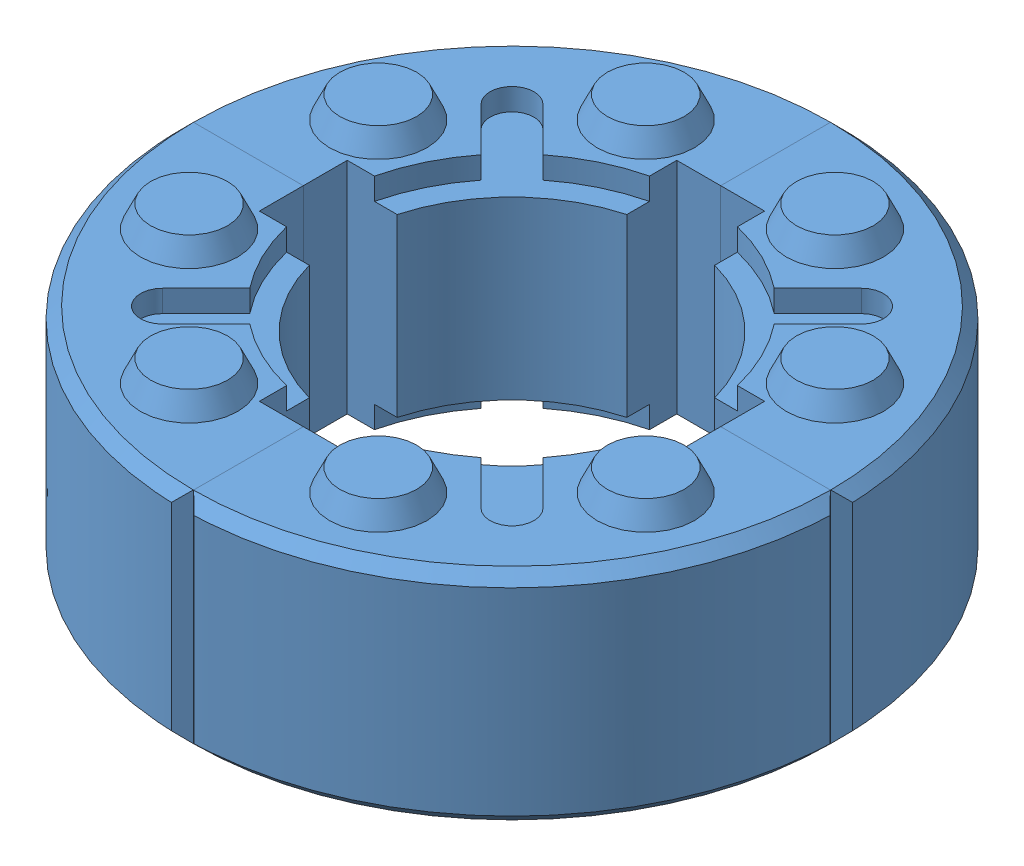
SolidWorks assembly Assem1, configuration Default. Lengths in mm.
Overall size (299.82 110 299.82).
4 component instances, 1 part files, 6 mates.
Components (placement in the parent):
- pillar brick 300dia-1: pillar brick 300dia [Default] at (-142.4139 -67.4386 119.003) size (149.91 110 149.91)
- pillar brick 300dia-2: pillar brick 300dia [Default] at (-142.4139 -67.4386 119.003) x (0 0 -1) z (1 0 0) size (149.91 110 149.91)
- pillar brick 300dia-3: pillar brick 300dia [Default] at (-142.4139 -67.4386 119.003) x (-1 0 0) z (0 0 -1) size (149.91 110 149.91)
- pillar brick 300dia-4: pillar brick 300dia [Default] at (-142.4139 -67.4386 119.003) x (0 0 1) z (-1 0 0) size (149.91 110 149.91)
Mates (geometry in assembly coordinates):
- Coincident8: coincident anti-aligned: line of pillar brick 300dia-1 through (-142.4139 32.5614 -25.9108) axis (0 0 1); line of pillar brick 300dia-2 through (-142.4139 32.5614 24.003) axis (0 0 -1)
- Coincident9: coincident aligned: circle of pillar brick 300dia-1; circle of pillar brick 300dia-2
- Coincident11: coincident anti-aligned: line of pillar brick 300dia-1 through (-47.4139 32.5614 119.003) axis (1 0 0); line of pillar brick 300dia-4 through (2.4998 32.5614 119.003) axis (-1 0 0)
- Coincident12: coincident aligned: circle of pillar brick 300dia-1; circle of pillar brick 300dia-4
- Coincident13: coincident anti-aligned: line of pillar brick 300dia-3 through (-142.4139 32.5614 263.9167) axis (0 0 -1); line of pillar brick 300dia-4 through (-142.4139 32.5614 214.003) axis (0 0 1)
- Coincident14: coincident aligned: circle of pillar brick 300dia-3; circle of pillar brick 300dia-4
